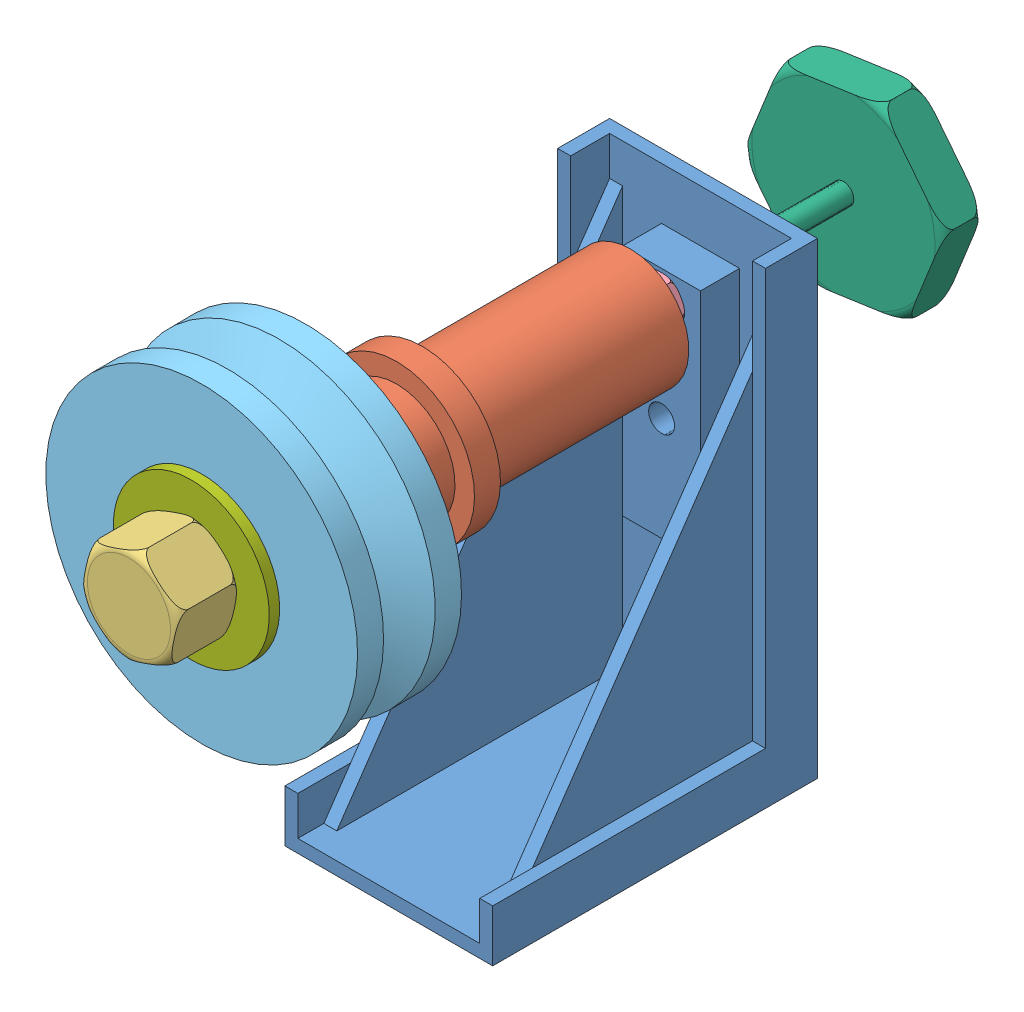
SolidWorks assembly Assem4, configuration Default. Lengths in mm.
Overall size (30.56 52.78 72.94).
7 component instances, 7 part files, 15 mates.
Components (placement in the parent):
- Bracket-1: Bracket [Default] at (14.6518 6.0213 35.8244) size (20 45 31.25)
- Bushing-1: Bushing [Default] at (14.6518 41.0213 41.9494) x (0 0 -1) z (0.955758 0.294155 0) size (31.25 15 15)
- Cop Screw-1: Cop Screw [Default] at (14.6518 41.0213 71.5744) x (-0.186042 -0.982542 0) z (0.982542 -0.186042 0) size (10.5 27.44 9.21)
- Nut-1: Nut [Default] at (14.6518 41.0213 24.8244) x (1 0 0) z (0 -1 0) size (5.25 3.19 4.58)
- Pulley-1: Pulley [Default] at (14.6518 41.0213 62.5744) x (0 0 -1) z (0.018749 -0.999824 0) size (10 30 30)
- Turn Screw-1: Turn Screw [Default] at (14.6518 41.0213 3.9494) x (0.164107 -0.986442 0) z (-0.986442 -0.164107 0) size (17.72 34.01 20.14)
- Washer-1: Washer [Default] at (14.6518 41.0213 68.0744) x (0 -1 0) z (1 0 0) size (15 1 15)
Mates (geometry in assembly coordinates):
- Coincident1: coincident anti-aligned: circle of Pulley-1; plane of Washer-1 through (14.6518 41.0213 67.5744) normal (0 0 -1)
- Coincident2: coincident anti-aligned: plane of Pulley-1 through (20.2758 41.1268 67.5744) normal (0 0 1); plane of Washer-1 through (14.6518 41.0213 67.5744) normal (0 0 -1)
- Concentric1: concentric aligned: circle of Pulley-1; cylinder of Washer-1 through (14.6518 41.0213 67.5744) axis (0 0 1) radius 1.875
- Coincident3: coincident anti-aligned: plane of Cop Screw-1 through (14.6518 41.0213 68.5744) normal (0 0 -1); plane of Washer-1 through (14.6518 41.0213 68.5744) normal (0 0 1)
- Concentric2: concentric anti-aligned: cylinder of Cop Screw-1 through (14.6518 41.0213 47.3244) axis (0 0 1) radius 2; circle of Washer-1
- Concentric6: concentric aligned: cylinder of Bushing-1 through (14.6518 41.0213 57.5744) axis (0 0 1) radius 5.625; cylinder of Pulley-1 through (14.6518 41.0213 67.5744) axis (0 0 1) radius 5.625
- Concentric9: concentric aligned: cylinder of Cop Screw-1 through (14.6518 41.0213 47.3244) axis (0 0 1) radius 2; cylinder of Nut-1 through (14.6518 41.0213 23.3244) axis (0 0 1) radius 1.25
- Coincident9: coincident aligned: circle of Bracket-1; circle of Nut-1
- Concentric10: concentric aligned: cylinder of Cop Screw-1 through (14.6518 41.0213 47.3244) axis (0 0 1) radius 2; cylinder of Nut-1 through (14.6518 41.0213 23.3244) axis (0 0 1) radius 1.25
- Coincident12: coincident anti-aligned: plane of Bushing-1 through (14.6518 41.0213 26.3244) normal (0 0 -1); plane of Nut-1 through (14.6518 41.0213 26.3244) normal (0 0 1)
- Concentric11: concentric aligned: cylinder of Bushing-1 through (14.6518 41.0213 35.8244) axis (0 0 1) radius 1.875; cylinder of Cop Screw-1 through (14.6518 41.0213 47.3244) axis (0 0 1) radius 2
- Coincident14: coincident anti-aligned: plane of Bushing-1 through (14.6518 41.0213 57.5744) normal (0 0 1); plane of Pulley-1 through (29.6491 41.3025 57.5744) normal (0 0 -1)
- Concentric12: concentric aligned: cylinder of Bracket-1 through (14.6518 41.0213 65.3244) axis (0 0 -1) radius 1.25; cylinder of Turn Screw-1 through (14.6518 41.0213 35.8244) axis (0 0 -1) radius 1
- Concentric13: concentric anti-aligned: circle of Bushing-1; circle of Turn Screw-1
- Coincident15: coincident anti-aligned: circle of Bushing-1; plane of Turn Screw-1 through (14.6518 41.0213 35.8244) normal (0 0 1)
